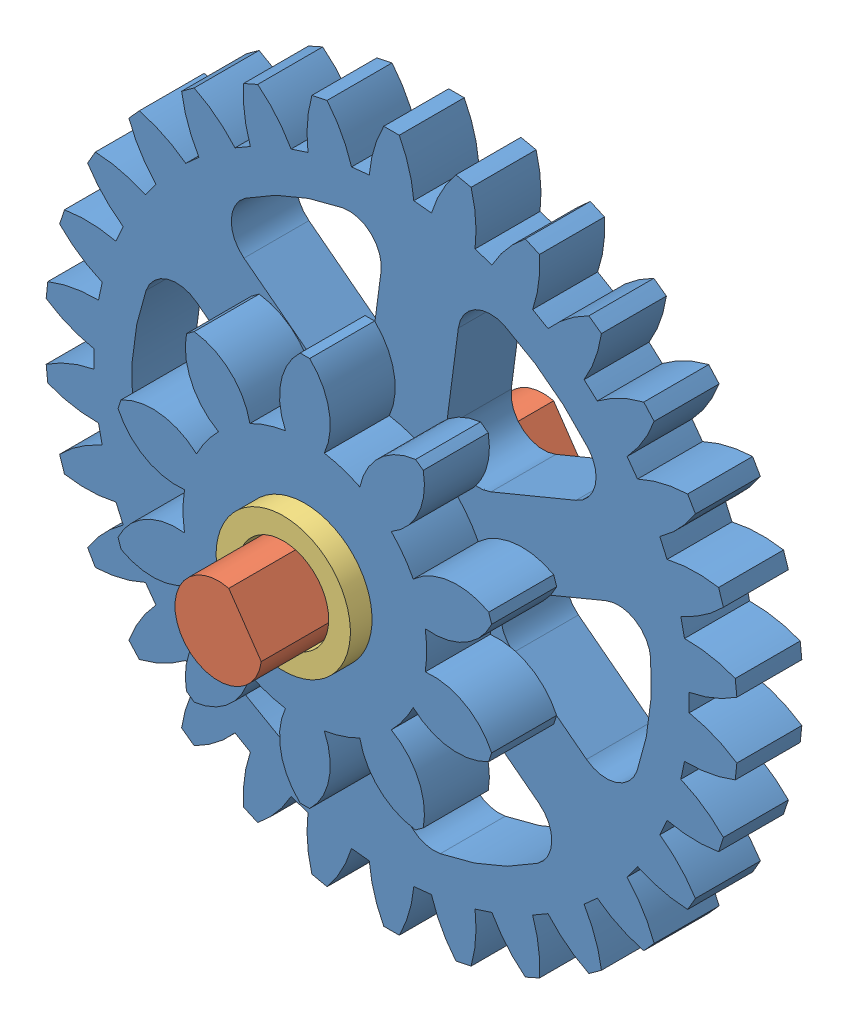
SolidWorks assembly SubAsmNum2, configuration Default. Lengths in mm.
Overall size (31.89 32 15).
6 component instances, 3 part files, 12 mates.
Components (placement in the parent):
- root_gear.-1: root_gear. [30T 1.0 Mod] at (11.2975 20.7352 20.6624) size (31.89 32 3)
- root_gear.-2: root_gear. [10T 1.5 Mod] at (11.2975 20.7352 24.6624) size (17.25 18 3)
- GearboxAxle-1: GearboxAxle [15mm] at (11.2975 20.7352 16.6624) x (0.926974 -0.375125 0) z (0 0 1) size (4 3.98 15)
- GearboxSpacer-1: GearboxSpacer [4.2 ID 1mm] at (11.2975 20.7352 27.6624) x (0.999935 -0.011387 0) z (0 0 1) size (6.2 6.2 1)
- GearboxSpacer-2: GearboxSpacer [4.2 ID 1mm] at (11.2975 20.7352 19.6624) size (6.2 6.2 1)
- GearboxSpacer-3: GearboxSpacer [4.2 ID 1mm] at (11.2975 20.7352 23.6624) x (0.999999 0.001194 0) z (0 0 1) size (6.2 6.2 1)
Mates (geometry in assembly coordinates):
- Concentric1: concentric aligned: cylinder of root_gear.-1 through (11.2975 20.7352 20.6624) axis (0 0 1) radius 2; cylinder of root_gear.-2 through (11.2975 20.7352 24.6624) axis (0 0 1) radius 2
- Coincident1: coincident aligned: plane of root_gear.-1 through (13.2831 20.4954 20.6624) normal (-0.823876 -0.56677 0); plane of root_gear.-2 through (13.2831 20.4954 24.6624) normal (-0.823876 -0.56677 0)
- Concentric2: concentric anti-aligned: cylinder of root_gear.-2 through (11.2975 20.7352 24.6624) axis (0 0 1) radius 2; cylinder of GearboxAxle-1 through (11.2975 20.7352 31.6624) axis (0 0 -1) radius 2
- Coincident2: coincident anti-aligned: plane of root_gear.-2 through (13.2831 20.4954 24.6624) normal (-0.823876 -0.56677 0); plane of GearboxAxle-1 through (11.7836 22.6752 31.6624) normal (0.823876 0.56677 0)
- Concentric3: concentric aligned: cylinder of GearboxAxle-1 through (11.2975 20.7352 31.6624) axis (0 0 -1) radius 2; cylinder of GearboxSpacer-3 through (11.2975 20.7352 24.6624) axis (0 0 -1) radius 2.1
- Concentric4: concentric aligned: cylinder of GearboxAxle-1 through (11.2975 20.7352 31.6624) axis (0 0 -1) radius 2; cylinder of GearboxSpacer-2 through (11.2975 20.7352 20.6624) axis (0 0 -1) radius 2.1
- Concentric5: concentric aligned: cylinder of GearboxAxle-1 through (11.2975 20.7352 31.6624) axis (0 0 -1) radius 2; cylinder of GearboxSpacer-1 through (11.2975 20.7352 28.6624) axis (0 0 -1) radius 2.1
- Coincident3: coincident anti-aligned: plane of root_gear.-1 through (11.2975 20.7352 23.6624) normal (0 0 1); plane of GearboxSpacer-3 through (11.2975 20.7352 23.6624) normal (0 0 -1)
- Coincident4: coincident anti-aligned: plane of root_gear.-1 through (11.2975 20.7352 20.6624) normal (0 0 -1); plane of GearboxSpacer-2 through (11.2975 20.7352 20.6624) normal (0 0 1)
- Coincident5: coincident anti-aligned: plane of root_gear.-2 through (11.2975 20.7352 27.6624) normal (0 0 1); plane of GearboxSpacer-1 through (11.2975 20.7352 27.6624) normal (0 0 -1)
- Coincident6: coincident anti-aligned: plane of root_gear.-2 through (11.2975 20.7352 24.6624) normal (0 0 -1); plane of GearboxSpacer-3 through (11.2975 20.7352 24.6624) normal (0 0 1)
- Distance2: distance = 3 mm aligned: plane of GearboxAxle-1 through (11.2975 20.7352 31.6624) normal (0 0 1); plane of GearboxSpacer-1 through (11.2975 20.7352 28.6624) normal (0 0 1)
